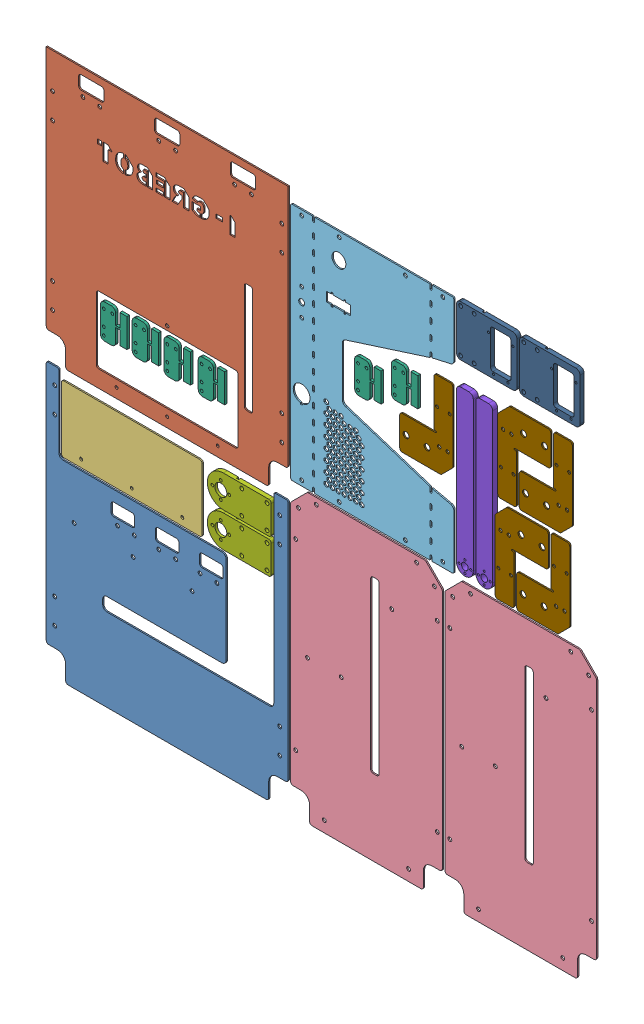
SolidWorks assembly carter_assy_2, configuration Default. Lengths in mm.
Overall size (653 643 7.5).
25 component instances, 10 part files, 39 mates.
Components (placement in the parent):
- 2018_carter_pt3-1: 2018_carter_pt3 [Default] at (-199.1215 -174.7012 38.5885) size (287 320 1.5)
- 2018_carter_pt2-1: 2018_carter_pt2 [Default] at (-199.1215 148.2988 38.5885) size (287 320 1.5)
- 2018_carter_pt5-1: 2018_carter_pt5 [Default] at (-181.1215 56.2988 38.5885) size (167 79 1.5)
- 2018_carter_pt1-2: 2018_carter_pt1 [Défaut] at (90.8785 -174.7012 38.5885) size (180 340 1.5)
- 2018_carter_pt1-3: 2018_carter_pt1 [Défaut] at (273.8785 -174.7012 38.5885) size (180 340 1.5)
- 2018_carter_pt7-1: 2018_carter_pt7 [Unfolded] at (276.2234 168.2988 19.4966) x (-1 0 0) z (0 1 0) size (193.76 1.5 284)
- WTB4_Mount_pt1-2: WTB4_Mount_pt1 [Unfolded] at (-115.2754 226.6948 41.5885) x (0 0 -1) z (-1 0 0) size (3 40.5 31.36)
- 2018_water_pt12-1: 2018_water_pt12 [Unfolded] at (21.8785 56.2988 40.0885) x (1 0 0) z (0 1 0) size (75.82 4.85 38)
- 2018_water_pt12-2: 2018_water_pt12 [Unfolded] at (21.8785 97.2988 40.0885) x (1 0 0) z (0 1 0) size (75.82 4.85 38)
- 2018_bee_pt1-1: 2018_bee_pt1 [Default] at (287.6345 172.4834 34.0885) size (20 192 6)
- 2018_bee_pt1-2: 2018_bee_pt1 [Default] at (310.6345 172.0106 34.0885) size (20 192 6)
- WTB4_Mount_pt1-8: WTB4_Mount_pt1 [Unfolded] at (-79.1144 227.2723 40.0885) x (0 0 -1) z (-1 0 0) size (3 40.5 31.36)
- WTB4_Mount_pt1-9: WTB4_Mount_pt1 [Unfolded] at (-41.4274 226.4254 40.0885) x (0 0 -1) z (-1 0 0) size (3 40.5 31.36)
- WTB4_Mount_pt1-10: WTB4_Mount_pt1 [Unfolded] at (-0.7762 226.4254 40.0885) x (0 0 -1) z (-1 0 0) size (3 40.5 31.36)
- Assemblage2^carter_assy_2-1: Assemblage2^carter_assy_2 [Default] at origin size (88.53 100 1.5) (virtual)
  - WTB4S Mount-1: WTB4S Mount [Unfold] at (398.1688 168.2988 38.5885) size (63.03 100 1.5)
  - WTB4S Mount-2: WTB4S Mount [Unfold] at (357.6345 268.2988 38.5885) x (-1 0 0) z (0 0 1) size (63.03 100 1.5)
- Assemblage2^carter_assy_2-2: Assemblage2^carter_assy_2 [Default] at (3.7699 106.059 0.75) size (88.53 100 1.5) (virtual)
  - WTB4S Mount-1: WTB4S Mount [Unfold] at (398.1688 168.2988 38.5885) size (63.03 100 1.5)
  - WTB4S Mount-2: WTB4S Mount [Unfold] at (357.6345 268.2988 38.5885) x (-1 0 0) z (0 0 1) size (63.03 100 1.5)
- WTB4_Mount_pt1-11: WTB4_Mount_pt1 [Unfolded] at (184.894 320.017 40.0885) x (0 0 -1) z (-1 0 0) size (3 40.5 31.36)
- WTB4_Mount_pt1-12: WTB4_Mount_pt1 [Unfolded] at (228.4911 336.984 40.0885) x (0 0 -1) z (-1 0 0) size (3 40.5 31.36)
- WTB4S Mount-3: WTB4S Mount [Unfold] at (259.3954 262.7126 38.5885) size (63.03 100 1.5)
- 2018_water_pt11-1: 2018_water_pt11 [Unfolded] at (313.4561 452.2988 7.0885) x (1 0 0) z (0 -1 0) size (71.82 4.85 60)
- 2018_water_pt11-2: 2018_water_pt11 [Unfolded] at (388.2777 452.2988 7.0885) x (1 0 0) z (0 -1 0) size (71.82 4.85 60)
Mates (geometry in assembly coordinates):
- Coïncidente1: coincident aligned: plane of 2018_carter_pt3-1 through (-199.1215 -174.7012 40.0885) normal (0 0 1); plane of 2018_carter_pt1-2 through (90.8785 -174.7012 40.0885) normal (0 0 1)
- Coïncidente2: coincident aligned: plane of 2018_carter_pt1-2 through (90.8785 -174.7012 40.0885) normal (0 0 1); plane of 2018_carter_pt1-3 through (273.8785 -174.7012 40.0885) normal (0 0 1)
- Coïncidente3: coincident aligned: plane of 2018_carter_pt1-2 through (90.8785 -174.7012 40.0885) normal (0 0 1); plane of 2018_carter_pt7-1 through (257.1315 452.2988 40.0885) normal (0 0 1)
- Coïncidente4: coincident aligned: plane of 2018_carter_pt3-1 through (-199.1215 -174.7012 40.0885) normal (0 0 1); plane of 2018_carter_pt2-1 through (-199.1215 148.2988 40.0885) normal (0 0 1)
- Coïncidente5: coincident aligned: plane of 2018_carter_pt3-1 through (-199.1215 -174.7012 40.0885) normal (0 0 1); plane of 2018_carter_pt5-1 through (-181.1215 56.2988 40.0885) normal (0 0 1)
- Distance1: distance = 3 mm anti-aligned: plane of 2018_carter_pt2-1 through (-199.1215 148.2988 40.0885) normal (0 -1 0); plane of 2018_carter_pt3-1 through (-199.1215 145.2988 40.0885) normal (0 1 0)
- Coïncidente6: coincident aligned: plane of 2018_carter_pt3-1 through (-199.1215 -174.7012 40.0885) normal (-1 0 0); plane of 2018_carter_pt2-1 through (-199.1215 148.2988 40.0885) normal (-1 0 0)
- Distance2: distance = 3 mm anti-aligned: plane of 2018_carter_pt5-1 through (-181.1215 56.2988 40.0885) normal (0 -1 0); plane of 2018_carter_pt3-1 through (-125.6215 53.2988 38.5885) normal (0 1 0)
- Distance3: distance = 3 mm anti-aligned: plane of 2018_carter_pt5-1 through (-181.1215 56.2988 40.0885) normal (-1 0 0); plane of 2018_carter_pt3-1 through (-184.1215 53.2988 38.5885) normal (1 0 0)
- Distance4: distance = 3 mm anti-aligned: plane of 2018_carter_pt1-2 through (90.8785 -174.7012 40.0885) normal (-1 0 0); plane of 2018_carter_pt3-1 through (87.8785 -174.7012 40.0885) normal (1 0 0)
- Coïncidente7: coincident aligned: plane of 2018_carter_pt3-1 through (-199.1215 -174.7012 40.0885) normal (0 -1 0); plane of 2018_carter_pt1-2 through (90.8785 -174.7012 40.0885) normal (0 -1 0)
- Coïncidente8: coincident aligned: plane of 2018_carter_pt1-2 through (90.8785 -174.7012 40.0885) normal (0 -1 0); plane of 2018_carter_pt1-3 through (273.8785 -174.7012 40.0885) normal (0 -1 0)
- Distance5: distance = 3 mm anti-aligned: plane of 2018_carter_pt1-3 through (273.8785 -174.7012 40.0885) normal (-1 0 0); plane of 2018_carter_pt1-2 through (270.8785 -174.7012 40.0885) normal (1 0 0)
- Distance6: distance = 3 mm anti-aligned: plane of 2018_carter_pt7-1 through (258.778 168.2988 39.0634) normal (0 -1 0); plane of 2018_carter_pt1-2 through (90.8785 165.2988 40.0885) normal (0 1 0)
- Distance7: distance = 3 mm anti-aligned: plane of 2018_carter_pt7-1 through (90.8785 452.2988 40.0885) normal (-1 0 0); plane of 2018_carter_pt2-1 through (87.8785 148.2988 40.0885) normal (1 0 0)
- Coïncidente9: coincident aligned: plane of 2018_carter_pt2-1 through (-199.1215 148.2988 40.0885) normal (0 0 1); plane of ? through (-135.2034 223.5613 40.0885) normal (0 0 1)
- Distance8: distance = 3 mm: plane of 2018_water_pt12-2 through (67.8785 135.2988 35.2385) normal (1 0 0); line of 2018_carter_pt3-1 through (70.8785 -71.7012 38.5885) axis (0 1 0)
- Distance9: distance = 3 mm anti-aligned: plane of 2018_water_pt12-1 through (67.8785 94.2988 35.2385) normal (1 0 0); plane of 2018_carter_pt3-1 through (70.8785 145.2988 38.5885) normal (-1 0 0)
- Distance10: distance = 3 mm anti-aligned: plane of 2018_water_pt12-1 through (21.207 56.2988 32.2385) normal (0 -1 0); plane of 2018_carter_pt3-1 through (-125.6215 53.2988 38.5885) normal (0 1 0)
- Distance11: distance = 3 mm anti-aligned: plane of 2018_water_pt12-1 through (24.207 94.2988 32.2385) normal (0 1 0); plane of 2018_water_pt12-2 through (21.207 97.2988 32.2385) normal (0 -1 0)
- Coïncidente10: coincident aligned: plane of 2018_carter_pt5-1 through (-181.1215 56.2988 40.0885) normal (0 0 1); plane of 2018_water_pt12-1 through (21.8785 94.2988 40.0885) normal (0 0 1)
- Coïncidente11: coincident aligned: plane of 2018_carter_pt5-1 through (-181.1215 56.2988 40.0885) normal (0 0 1); plane of 2018_water_pt12-2 through (21.8785 135.2988 40.0885) normal (0 0 1)
- Coïncidente12: coincident aligned: plane of 2018_carter_pt7-1 through (257.1315 452.2988 40.0885) normal (0 0 1); plane of 2018_bee_pt1-1 through (287.6345 172.4834 40.0885) normal (0 0 1)
- Distance12: distance = 3 mm anti-aligned: plane of 2018_bee_pt1-1 through (287.6345 172.4834 40.0885) normal (-1 0 0); plane of 2018_carter_pt7-1 through (284.6345 452.2988 38.5885) normal (1 0 0)
- Distance13: distance = 3 mm anti-aligned: plane of 2018_bee_pt1-1 through (307.6345 172.4834 40.0885) normal (1 0 0); plane of 2018_bee_pt1-2 through (310.6345 172.0106 40.0885) normal (-1 0 0)
- Coïncidente13: coincident aligned: plane of 2018_bee_pt1-1 through (287.6345 172.4834 40.0885) normal (0 0 1); plane of 2018_bee_pt1-2 through (310.6345 172.0106 40.0885) normal (0 0 1)
- Coïncidente16: coincident aligned: plane of 2018_bee_pt1-2 through (310.6345 172.0106 40.0885) normal (0 0 1); plane of Assemblage2^carter_assy_2-1/WTB4S Mount-2 through (357.6345 268.2988 40.0885) normal (0 0 1)
- Distance19: distance = 3 mm anti-aligned: plane of Assemblage2^carter_assy_2-1/WTB4S Mount-2 through (333.6345 168.2988 40.0885) normal (-1 0 0); plane of 2018_bee_pt1-2 through (330.6345 172.0106 40.0885) normal (1 0 0)
- Distance21: distance = 3 mm anti-aligned: plane of 2018_carter_pt1-3 through (273.8785 165.2988 40.0885) normal (0 1 0); plane of Assemblage2^carter_assy_2-1/WTB4S Mount-1 through (399.1345 168.2988 40.0885) normal (0 -1 0)
- Coïncidente17: coincident aligned: plane of 2018_carter_pt7-1 through (257.1315 452.2988 40.0885) normal (0 0 1); plane of WTB4S Mount-3 through (259.3954 262.7126 40.0885) normal (0 0 1)
- Coïncidente18: coincident aligned: plane of 2018_carter_pt7-1 through (257.1315 452.2988 40.0885) normal (0 0 1); plane of WTB4_Mount_pt1-12 through (210.4911 336.984 40.0885) normal (0 0 1)
- Coïncidente19: coincident aligned: plane of 2018_carter_pt7-1 through (257.1315 452.2988 40.0885) normal (0 0 1); plane of WTB4_Mount_pt1-11 through (166.894 320.017 40.0885) normal (0 0 1)
- Parallèle1: parallel aligned: plane of 2018_carter_pt7-1 through (257.1315 452.2988 40.0885) normal (0 0 1); plane of 2018_water_pt11-1 through (313.4561 392.2988 40.0885) normal (0 0 1)
- Coïncidente20: coincident aligned: plane of 2018_carter_pt7-1 through (257.1315 452.2988 40.0885) normal (0 0 1); plane of 2018_water_pt11-1 through (313.4561 392.2988 40.0885) normal (0 0 1)
- Distance22: distance = 3 mm anti-aligned: plane of 2018_carter_pt7-1 through (284.6345 452.2988 38.5885) normal (1 0 0); plane of 2018_water_pt11-1 through (287.6345 392.2988 35.2385) normal (-1 0 0)
- Coïncidente21: coincident aligned: plane of 2018_carter_pt7-1 through (116.7351 452.2988 39.0634) normal (0 1 0); plane of 2018_water_pt11-1 through (315.7845 452.2988 32.2385) normal (0 1 0)
- Coïncidente22: coincident aligned: plane of 2018_water_pt11-1 through (315.7845 452.2988 32.2385) normal (0 1 0); plane of 2018_water_pt11-2 through (390.6061 452.2988 32.2385) normal (0 1 0)
- Distance23: distance = 3 mm anti-aligned: plane of 2018_water_pt11-2 through (362.4561 392.2988 35.2385) normal (-1 0 0); plane of 2018_water_pt11-1 through (359.4561 392.2988 40.0885) normal (1 0 0)
- Coïncidente23: coincident aligned: plane of 2018_water_pt11-1 through (313.4561 392.2988 40.0885) normal (0 0 1); plane of 2018_water_pt11-2 through (388.2777 392.2988 40.0885) normal (0 0 1)
